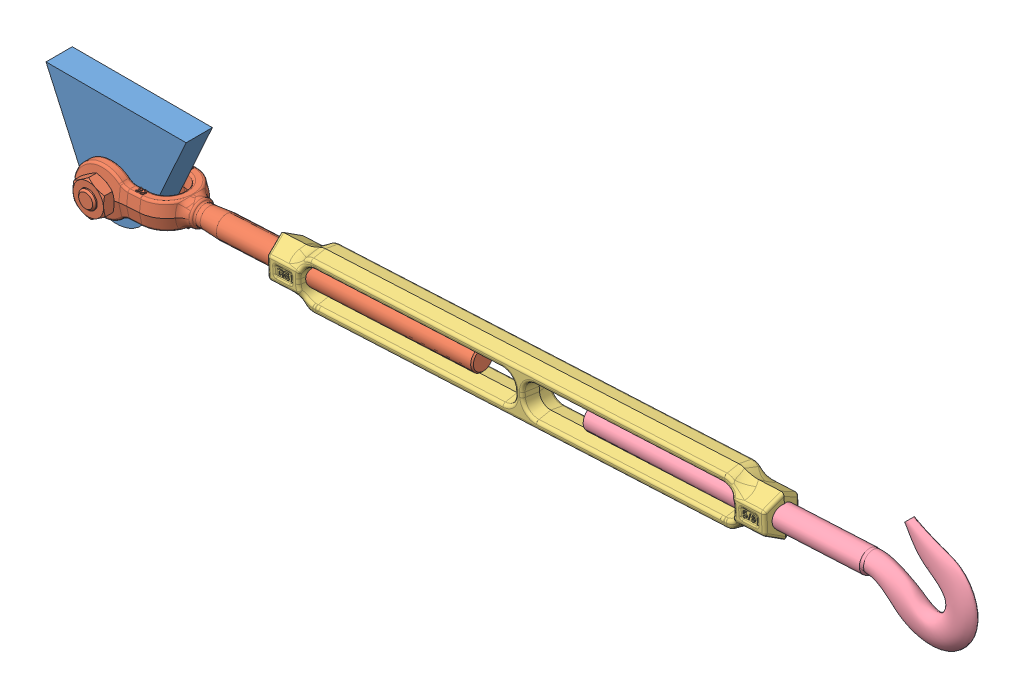
SolidWorks assembly 000020_REVB_BOOM STOWAGE HOOK, configuration Default. Lengths in mm.
4 component instances, 4 part files, 16 mates.
Components (placement in the parent):
- 000020-01_REVB_PADEYE-1: 000020-01_REVB_PADEYE [RIGGING PADEYE X 0.75 THK] x (0 -1 0) z (1 0 0) size (76.2 19.05 101.6)
- 000020-02_REVA_0.625 X 12 TURNBUCKLE JAW-1: 000020-02_REVA_0.625 X 12 TURNBUCKLE JAW [Default] at (0 -50.8 0) x (-0.998772 -0.049551 0) z (0.049551 -0.998772 0) size (277.35 62.19 33.45)
- 000020-03_REVA_0.625 X 12 TURNBUCKLE BODY-1: 000020-03_REVA_0.625 X 12 TURNBUCKLE BODY [Default] at (293.1357 -36.2569 0) x (0.998772 0.049551 0) z (0 0 1) size (365.25 38.13 30.73)
- 000020-04_REVA_0.625 X 12 TURNBUCKLE HOOK-1: 000020-04_REVA_0.625 X 12 TURNBUCKLE HOOK [Default] at (394.6109 -31.2225 0) x (0.998772 0.049551 0) z (0 0 1) size (278.67 74.01 21.42)
Mates (geometry in assembly coordinates):
- Concentric24: concentric anti-aligned: cylinder of 000020-01_REVB_PADEYE-1 through (0 -50.8 0) axis (0 0 -1) radius 7.1437; cylinder of 000020-02_REVA_0.625 X 12 TURNBUCKLE JAW-1 through (0 -50.8 -22.4001) axis (0 0 1) radius 6.35
- Coincident258: coincident aligned: plane of 000020-01_REVB_PADEYE-1; plane of 000020-02_REVA_0.625 X 12 TURNBUCKLE JAW-1
- Coincident259: coincident anti-aligned: plane of 000020-01_REVB_PADEYE-1; plane of 000020-03_REVA_0.625 X 12 TURNBUCKLE BODY-1 through (280.4513 -36.8862 0) normal (0 0 1)
- Coincident260: coincident anti-aligned: plane of 000020-01_REVB_PADEYE-1; plane of 000020-04_REVA_0.625 X 12 TURNBUCKLE HOOK-1 through (381.9265 -31.8518 0) normal (0 0 1)
- Concentric25: concentric aligned: cylinder of 000020-02_REVA_0.625 X 12 TURNBUCKLE JAW-1 through (48.5678 -48.3904 0) axis (0.998772 0.049551 0) radius 8.001; cylinder of 000020-03_REVA_0.625 X 12 TURNBUCKLE BODY-1 through (132.5512 -44.2238 0) axis (0.998772 0.049551 0) radius 6.731
- Distance26: distance = 146.05 mm: point of 000020-03_REVA_0.625 X 12 TURNBUCKLE BODY-1; plane of 000020-02_REVA_0.625 X 12 TURNBUCKLE JAW-1 through (256.6046 -38.0693 0) normal (0.998772 0.049551 0)
- Concentric26: concentric aligned: cylinder of 000020-02_REVA_0.625 X 12 TURNBUCKLE JAW-1 through (48.5678 -48.3904 0) axis (0.998772 0.049551 0) radius 8.001; cylinder of 000020-04_REVA_0.625 X 12 TURNBUCKLE HOOK-1 through (682.027 -16.9631 0) axis (0.998772 0.049551 0) radius 7.9375
- Coincident291: coincident anti-aligned: plane of 000020-02_REVA_0.625 X 12 TURNBUCKLE JAW-1 through (0 -50.8 0) normal (0.049551 -0.998772 0); plane of 000020-03_REVA_0.625 X 12 TURNBUCKLE BODY-1
- Coincident292: coincident anti-aligned: plane of 000020-02_REVA_0.625 X 12 TURNBUCKLE JAW-1; plane of 000020-03_REVA_0.625 X 12 TURNBUCKLE BODY-1 through (280.4513 -36.8862 0) normal (0 0 1)
- Coincident288: coincident aligned: plane of 000020-03_REVA_0.625 X 12 TURNBUCKLE BODY-1 through (280.4513 -36.8862 0) normal (0 0 1); plane of 000020-04_REVA_0.625 X 12 TURNBUCKLE HOOK-1 through (381.9265 -31.8518 0) normal (0 0 1)
- Coincident289: coincident aligned: plane of 000020-03_REVA_0.625 X 12 TURNBUCKLE BODY-1; plane of 000020-04_REVA_0.625 X 12 TURNBUCKLE HOOK-1
- Distance30: distance = 101.6 mm aligned: plane of 000020-03_REVA_0.625 X 12 TURNBUCKLE BODY-1; plane of 000020-04_REVA_0.625 X 12 TURNBUCKLE HOOK-1
- Coincident295: coincident aligned: plane of 000020-01_REVB_PADEYE-1 through (-50.8 0 0) normal (0 1 0); plane of assembly through (0 0 0) normal (0 1 0)
- Coincident296: coincident aligned: plane of 000020-01_REVB_PADEYE-1 through (0 0 0) normal (1 0 0); plane of assembly through (0 0 0) normal (1 0 0)
- Coincident297: coincident anti-aligned: plane of 000020-01_REVB_PADEYE-1; plane of assembly through (0 0 0) normal (0 0 1)
- Coincident298: coincident anti-aligned: plane of 000020-02_REVA_0.625 X 12 TURNBUCKLE JAW-1; plane of assembly through (0 0 0) normal (1 0 0)
